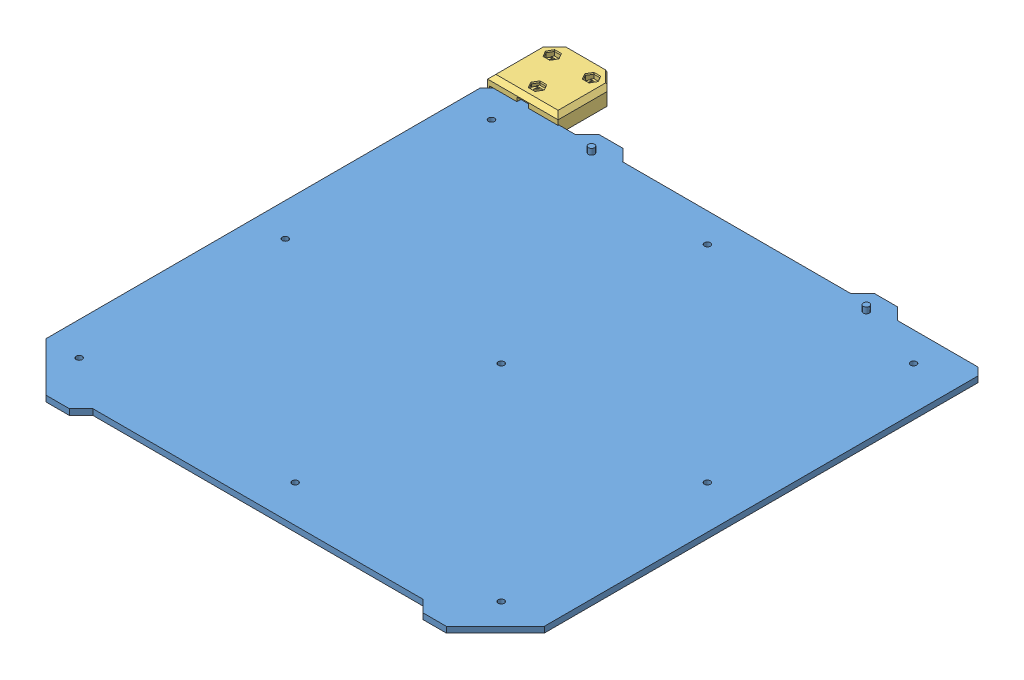
SolidWorks assembly Headbed Assembly, configuration Default. Lengths in mm.
Overall size (253.8 13.6 281.4).
12 component instances, 4 part files, 25 mates.
Components (placement in the parent):
- MK52 Bed-1: MK52 Bed [Default] at (-64.502 153.1745 327.7347) size (253.8 6 264.25)
- 6x6x3t spacer-1: 6x6x3t spacer [Default] at (62.498 147.1745 212.6933) size (6 6 6)
- 6x6x3t spacer-2: 6x6x3t spacer [Default] at (62.498 147.1745 107.6933) size (6 6 6)
- 6x6x3t spacer-3: 6x6x3t spacer [Default] at (-47.502 147.1745 317.6933) size (6 6 6)
- 6x6x3t spacer-4: 6x6x3t spacer [Default] at (-47.502 147.1745 107.6933) x (0.97497 0 -0.222336) z (0.222336 0 0.97497) size (6 6 6)
- 6x6x3t spacer-5: 6x6x3t spacer [Default] at (167.498 147.1745 317.6933) size (6 6 6)
- 6x6x3t spacer-6: 6x6x3t spacer [Default] at (167.498 147.1745 212.6933) size (6 6 6)
- 6x6x3t spacer-7: 6x6x3t spacer [Default] at (167.498 147.1745 107.6933) x (0.999855 0 0.017002) z (-0.017002 0 0.999855) size (6 6 6)
- 6x6x3t spacer-8: 6x6x3t spacer [Default] at (62.498 147.1745 317.6933) size (6 6 6)
- 6x6x3t spacer-9: 6x6x3t spacer [Default] at (-47.502 147.1745 212.6933) size (6 6 6)
- heatbed-cable-cover top-1: heatbed-cable-cover top [Default] at (-46.0021 152.1745 93.2347) x (1 0 0) z (0 1 0) size (36 32 8.6)
- heatbed-cable-cover bottom-1: heatbed-cable-cover bottom [Default] at (-46.0021 157.6745 113.2347) x (-1 0 0) z (0 -1 0) size (30 16.5 6)
Mates (geometry in assembly coordinates):
- Concentric1: concentric anti-aligned: circle of MK52 Bed-1; cylinder of 6x6x3t spacer-3 through (-47.502 153.1745 317.6933) axis (0 -1 0) radius 1.75
- Concentric2: concentric anti-aligned: circle of MK52 Bed-1; cylinder of 6x6x3t spacer-8 through (62.498 153.1745 317.6933) axis (0 -1 0) radius 1.75
- Concentric3: concentric anti-aligned: cylinder of MK52 Bed-1 through (167.498 153.1745 317.6933) axis (0 1 0) radius 1.55; cylinder of 6x6x3t spacer-5 through (167.498 153.1745 317.6933) axis (0 -1 0) radius 1.75
- Concentric4: concentric anti-aligned: circle of MK52 Bed-1; circle of 6x6x3t spacer-9
- Concentric5: concentric anti-aligned: circle of MK52 Bed-1; circle of 6x6x3t spacer-1
- Concentric6: concentric aligned: circle of MK52 Bed-1; circle of 6x6x3t spacer-6
- Concentric7: concentric anti-aligned: circle of MK52 Bed-1; circle of 6x6x3t spacer-4
- Concentric8: concentric anti-aligned: circle of MK52 Bed-1; circle of 6x6x3t spacer-2
- Concentric9: concentric aligned: circle of MK52 Bed-1; circle of 6x6x3t spacer-7
- Coincident1: coincident anti-aligned: plane of MK52 Bed-1 through (-64.502 153.1745 327.7347) normal (0 -1 0); plane of 6x6x3t spacer-8 through (62.498 153.1745 317.6933) normal (0 1 0)
- Coincident2: coincident anti-aligned: plane of MK52 Bed-1 through (-64.502 153.1745 327.7347) normal (0 -1 0); plane of 6x6x3t spacer-5 through (167.498 153.1745 317.6933) normal (0 1 0)
- Coincident3: coincident anti-aligned: plane of MK52 Bed-1 through (-64.502 153.1745 327.7347) normal (0 -1 0); plane of 6x6x3t spacer-3 through (-47.502 153.1745 317.6933) normal (0 1 0)
- Coincident4: coincident anti-aligned: plane of MK52 Bed-1 through (-64.502 153.1745 327.7347) normal (0 -1 0); plane of 6x6x3t spacer-9 through (-47.502 153.1745 212.6933) normal (0 1 0)
- Coincident5: coincident anti-aligned: plane of MK52 Bed-1 through (-64.502 153.1745 327.7347) normal (0 -1 0); plane of 6x6x3t spacer-1 through (62.498 153.1745 212.6933) normal (0 1 0)
- Coincident6: coincident anti-aligned: plane of MK52 Bed-1 through (-64.502 153.1745 327.7347) normal (0 -1 0); plane of 6x6x3t spacer-2 through (62.498 153.1745 107.6933) normal (0 1 0)
- Coincident7: coincident anti-aligned: plane of MK52 Bed-1 through (-64.502 153.1745 327.7347) normal (0 -1 0); plane of 6x6x3t spacer-6 through (167.498 153.1745 212.6933) normal (0 1 0)
- Coincident8: coincident anti-aligned: plane of MK52 Bed-1 through (-64.502 153.1745 327.7347) normal (0 -1 0); plane of 6x6x3t spacer-4 through (-47.502 153.1745 107.6933) normal (0 1 0)
- Coincident9: coincident anti-aligned: plane of MK52 Bed-1 through (-64.502 153.1745 327.7347) normal (0 -1 0); plane of 6x6x3t spacer-7 through (167.498 153.1745 107.6933) normal (0 1 0)
- Concentric10: concentric aligned: circle of MK52 Bed-1; cylinder of heatbed-cable-cover top-1 through (-46.0021 155.1745 85.7347) axis (0 1 0) radius 1.6
- Concentric11: concentric: cylinder of heatbed-cable-cover top-1 through (-56.0021 152.1745 68.2347) axis (0 1 0) radius 1.6; circle of heatbed-cable-cover bottom-1
- Concentric12: concentric: cylinder of heatbed-cable-cover top-1 through (-36.0021 152.1745 68.2347) axis (0 1 0) radius 1.6; cylinder of heatbed-cable-cover bottom-1 through (-36.0021 91.4626 68.2347) axis (0 1 0) radius 1.6
- Coincident10: coincident anti-aligned: plane of MK52 Bed-1 through (-64.502 156.1745 327.7347) normal (0 1 0); plane of heatbed-cable-cover top-1 through (-35.2394 156.1745 100.3091) normal (0 -1 0)
- Parallel1: parallel aligned: plane of MK52 Bed-1 through (-64.402 156.1745 327.7347) normal (-1 0 0); plane of heatbed-cable-cover top-1 through (-64.0021 152.1745 93.2347) normal (-1 0 0)
- Parallel2: parallel: plane of heatbed-cable-cover top-1 through (-64.0021 152.1745 93.2347) normal (-1 0 0); plane of heatbed-cable-cover bottom-1 through (-61.0021 91.4626 77.7347) normal (-1 0 0)
- Coincident12: coincident anti-aligned: plane of heatbed-cable-cover top-1 through (-61.0021 155.1745 78.2347) normal (0 -1 0); plane of heatbed-cable-cover bottom-1 through (-61.0021 155.1745 77.7347) normal (0 1 0)
